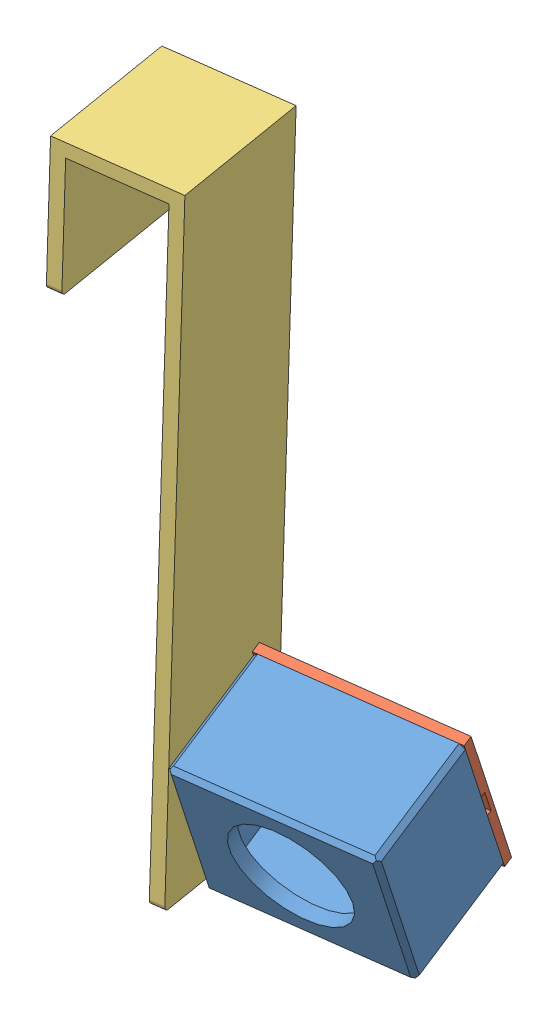
SolidWorks assembly Сборка1, configuration По умолчанию. Lengths in mm.
Overall size (73.78 142.14 44.76).
3 component instances, 3 part files, 5 mates.
Components (placement in the parent):
- Бокс-1: Бокс [По умолчанию] at (52.9519 37.3643 34.3722) x (-0.986286 0.029681 0.162356) z (-0.140132 0.369117 -0.918758) size (46 33 25)
- Крышка-1: Крышка [По умолчанию] at (49.5887 46.2231 12.322) x (0.986286 -0.029681 -0.162356) z (0.140132 -0.369117 0.918758) size (41 33 4)
- Крюк-1: Крюк [По умолчанию] at (26.9897 124.7652 14.23) x (0.986286 -0.029681 -0.162356) z (0.162356 -0.002426 0.986729) size (26 140 30)
Mates (geometry in assembly coordinates):
- Совпадение2: coincident anti-aligned: plane of Бокс-1 through (49.869 45.4849 14.1596) normal (-0.140132 0.369117 -0.918758); plane of Крышка-1 through (49.869 45.4849 14.1596) normal (0.140132 -0.369117 0.918758)
- Совпадение3: coincident aligned: plane of Бокс-1 through (70.0878 44.8764 10.8313) normal (0.986286 -0.029681 -0.162356); plane of Крышка-1 through (71.5266 60.2034 16.7695) normal (0.986286 -0.029681 -0.162356)
- Совпадение4: coincident aligned: plane of Бокс-1 through (48.4302 30.1579 8.2213) normal (-0.087198 -0.928909 -0.359895); plane of Крышка-1 through (28.2113 30.7663 11.5496) normal (-0.087198 -0.928909 -0.359895)
- Концентричный1: concentric anti-aligned: cylinder of Бокс-1 through (31.3317 41.6639 28.513) axis (-0.986286 0.029681 0.162356) radius 9; cylinder of Крюк-1 through (0.3327 42.5968 33.6158) axis (0.986286 -0.029681 -0.162356) radius 10.25
- Совпадение5: coincident: cone of Бокс-1 through (31.3317 41.6639 28.513) axis (-0.986286 0.029681 0.162356); circle of Крюк-1
